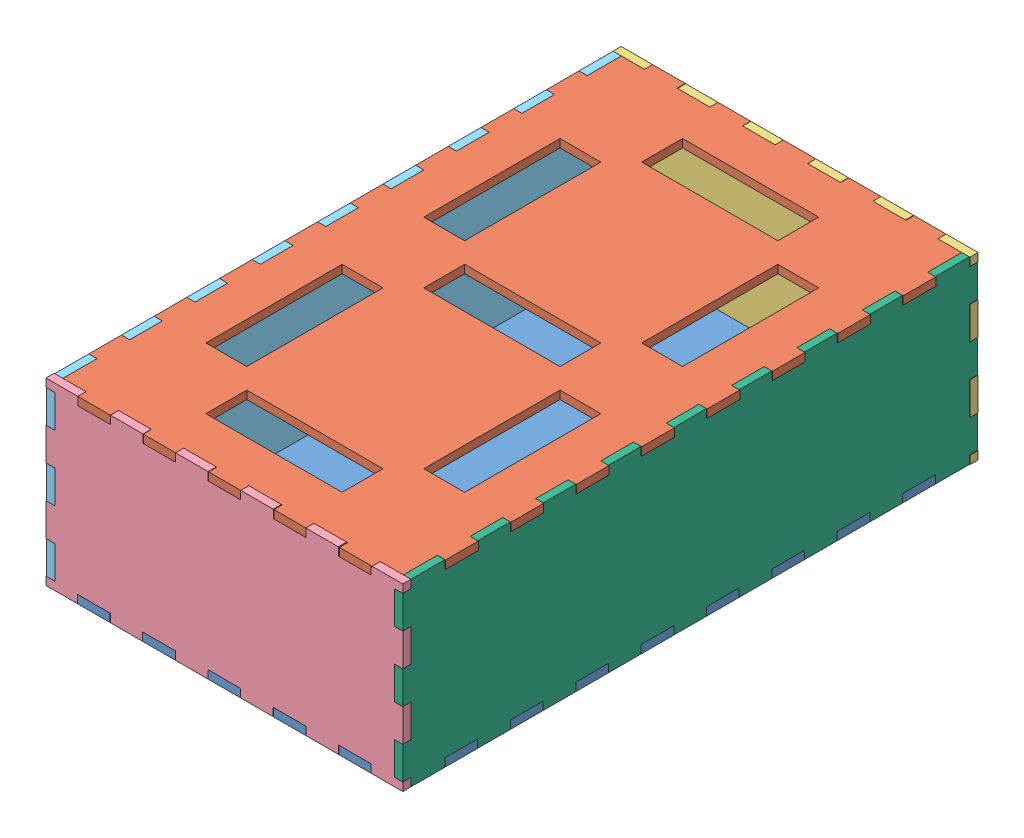
SolidWorks assembly 3mm_Assem1, configuration Default. Lengths in mm.
Overall size (131.21 66 211).
6 component instances, 6 part files, 19 mates.
Components (placement in the parent):
- BOTTOM_PLANE-1: BOTTOM_PLANE [Default] at (66.5623 93.9614 185.2459) size (131 3 211)
- TOP_PLANE-1: TOP_PLANE [Default] at (66.7755 156.9614 185.2459) size (131 3 211)
- BACK_PLANE-1: BACK_PLANE [Default] at (66.7183 90.9614 79.7459) size (131 66 3)
- FRONT_PLANE-1: FRONT_PLANE [Default] at (66.5337 90.9614 287.7459) size (131 66 3)
- LEFT_SIDE_PLANE-1: LEFT_SIDE_PLANE [Default] at (4.2755 24.2257 461.692) x (0 0 1) z (-1 0 0) size (211 66 3)
- RIGHT_SIDE_PLANE-1: RIGHT_SIDE_PLANE [Default] at (129.0623 24.2251 -91.2001) x (0 0 -1) z (1 0 0) size (211 66 3)
Mates (geometry in assembly coordinates):
- Coincident5: coincident anti-aligned: plane of BOTTOM_PLANE-1 through (66.5623 96.9614 185.2459) normal (0 1 0); plane of BACK_PLANE-1 through (66.7183 96.9614 82.7459) normal (0 -1 0)
- Coincident6: coincident anti-aligned: plane of BOTTOM_PLANE-1 through (4.0623 96.9614 82.7459) normal (0 0 -1); plane of BACK_PLANE-1 through (66.7183 90.9614 82.7459) normal (0 0 1)
- Coincident7: coincident anti-aligned: plane of BOTTOM_PLANE-1 through (120.5623 93.9614 82.7459) normal (1 0 0); plane of BACK_PLANE-1 through (120.5623 90.9614 82.7459) normal (-1 0 0)
- Parallel1: parallel anti-aligned: plane of BOTTOM_PLANE-1 through (66.5623 96.9614 185.2459) normal (0 1 0); plane of TOP_PLANE-1 through (66.7755 156.9614 185.2459) normal (0 -1 0)
- Parallel2: parallel aligned: plane of BOTTOM_PLANE-1 through (129.0623 96.9614 287.7459) normal (1 0 0); plane of TOP_PLANE-1 through (129.2755 159.9614 287.7459) normal (1 0 0)
- Parallel3: parallel aligned: plane of BOTTOM_PLANE-1 through (66.5623 93.9614 290.7459) normal (0 0 1); plane of TOP_PLANE-1 through (66.7755 156.9614 290.7459) normal (0 0 1)
- Coincident11: coincident anti-aligned: plane of TOP_PLANE-1 through (66.7755 156.9614 185.2459) normal (0 -1 0); plane of BACK_PLANE-1 through (66.7183 156.9614 82.7459) normal (0 1 0)
- Coincident12: coincident anti-aligned: plane of TOP_PLANE-1 through (4.2755 159.9614 82.7459) normal (0 0 -1); plane of BACK_PLANE-1 through (66.7183 90.9614 82.7459) normal (0 0 1)
- Coincident13: coincident anti-aligned: plane of TOP_PLANE-1 through (60.7755 156.9614 185.2459) normal (-1 0 0); plane of BACK_PLANE-1 through (60.7755 90.9614 82.7459) normal (1 0 0)
- Coincident14: coincident anti-aligned: plane of TOP_PLANE-1 through (66.7755 156.9614 185.2459) normal (0 -1 0); plane of FRONT_PLANE-1 through (66.5337 156.9614 290.7459) normal (0 1 0)
- Coincident15: coincident anti-aligned: plane of TOP_PLANE-1 through (4.2755 159.9614 287.7459) normal (0 0 1); plane of FRONT_PLANE-1 through (66.5337 90.9614 287.7459) normal (0 0 -1)
- Coincident16: coincident anti-aligned: plane of TOP_PLANE-1 through (12.7755 156.9614 290.7459) normal (-1 0 0); plane of FRONT_PLANE-1 through (12.7755 90.9614 290.7459) normal (1 0 0)
- Coincident17: coincident anti-aligned: plane of TOP_PLANE-1 through (4.2755 159.9614 287.7459) normal (-1 0 0); plane of LEFT_SIDE_PLANE-1 through (4.2755 24.2257 461.692) normal (1 0 0)
- Coincident18: coincident anti-aligned: plane of FRONT_PLANE-1 through (66.5337 90.9614 287.7459) normal (0 0 -1); plane of LEFT_SIDE_PLANE-1 through (1.2755 24.2257 287.7459) normal (0 0 1)
- Coincident19: coincident anti-aligned: plane of BACK_PLANE-1 through (66.7183 156.9614 76.7459) normal (0 -1 0); plane of LEFT_SIDE_PLANE-1 through (4.2755 156.9614 82.7459) normal (0 1 0)
- Parallel4: parallel anti-aligned: plane of LEFT_SIDE_PLANE-1 through (4.2755 24.2257 461.692) normal (1 0 0); plane of RIGHT_SIDE_PLANE-1 through (129.0623 24.2251 -91.2001) normal (-1 0 0)
- Coincident22: coincident anti-aligned: plane of BACK_PLANE-1 through (66.7183 90.9614 82.7459) normal (0 0 1); plane of RIGHT_SIDE_PLANE-1 through (132.0623 24.2251 82.7459) normal (0 0 -1)
- Coincident23: coincident anti-aligned: plane of BOTTOM_PLANE-1 through (66.5623 96.9614 185.2459) normal (0 1 0); plane of RIGHT_SIDE_PLANE-1 through (132.0623 96.9614 -91.2001) normal (0 -1 0)
- Coincident24: coincident anti-aligned: plane of BOTTOM_PLANE-1 through (129.0623 96.9614 287.7459) normal (1 0 0); plane of RIGHT_SIDE_PLANE-1 through (129.0623 24.2251 -91.2001) normal (-1 0 0)
